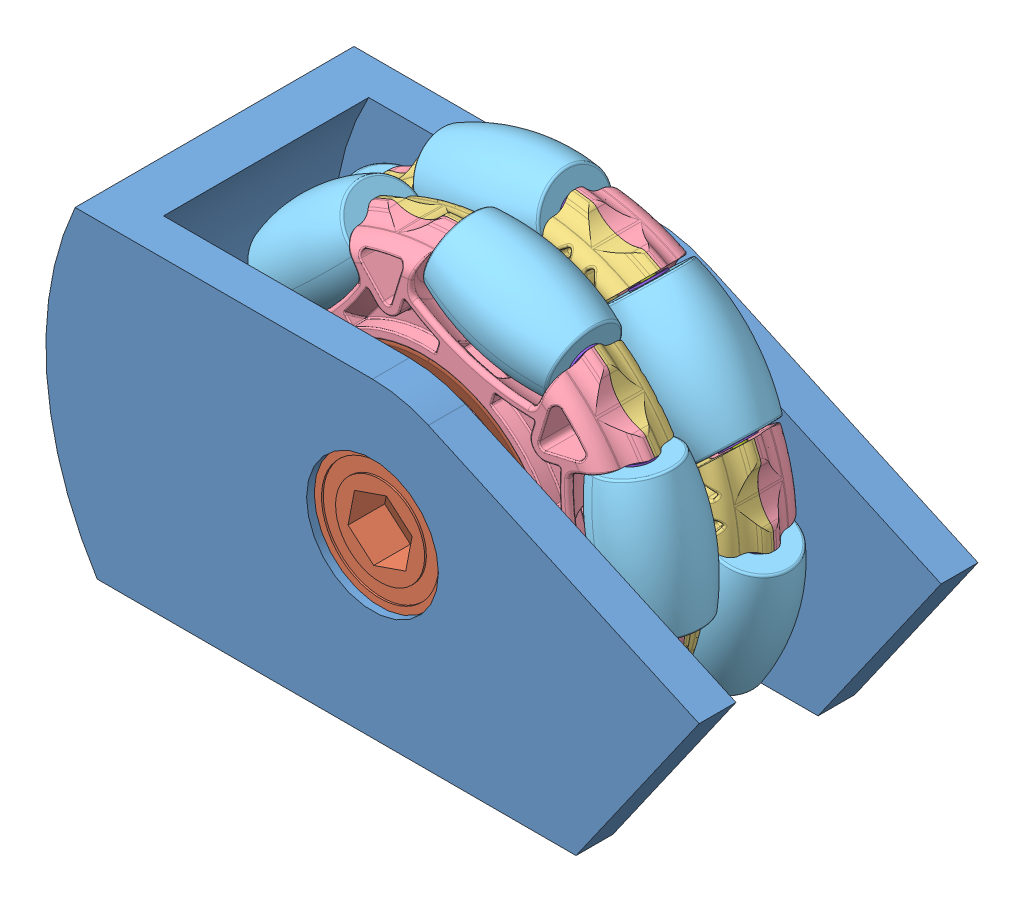
SolidWorks assembly Assem3, configuration Default. Lengths in mm.
Overall size (153.65 153.65 60.45).
87 component instances, 11 part files, 11 mates.
Components (placement in the parent):
- OuterWheelBase-1: OuterWheelBase [Default] at (20.5301 83.2781 119.3728) size (141.6 67.39 60.45)
- 0_500_Hex_ID_x_1_125_OD_x_0_313_WD_Flanged_Bearing_v2_217-3875 (1).step-1: 0_500_Hex_ID_x_1_125_OD_x_0_313_WD_Flanged_Bearing_v2_217-3875 (1).step [Default] at (20.5301 83.2781 125.7228) x (0.944813 0.327609 0) z (-0.327609 0.944813 0) size (31.12 7.94 31.12)
- 0_500_Hex_ID_x_1_125_OD_x_0_313_WD_Flanged_Bearing_v2_217-3875 (1).step-2: 0_500_Hex_ID_x_1_125_OD_x_0_313_WD_Flanged_Bearing_v2_217-3875 (1).step [Default] at (20.5301 83.2781 68.5728) x (0.995254 0.097311 0) z (0.097311 -0.995254 0) size (31.12 7.94 31.12)
- 4_Omni-Directional_Wheel_v2_276-6194.STEP-1: 4_Omni-Directional_Wheel_v2_276-6194.STEP [Default] at (20.5301 83.2781 97.2714) x (0.956229 -0.29262 0) z (0 0 1) size (126.87 125.33 42.82)
  - 217-6194-002 Rev5.STEP-1: 217-6194-002 Rev5.STEP [Default] at origin size (94.42 94.42 19.26)
  - 217-6194-003 Rev8.STEP-1: 217-6194-003 Rev8.STEP [Default] at (0 0 9.525) size (94.42 90.2 19.97)
  - 217-6194-003 Rev8.STEP-2: 217-6194-003 Rev8.STEP [Default] at (0 0 -9.525) x (-0.866025 0.5 0) z (0 0 -1) size (94.42 90.2 19.97)
  - 217-6194-001 Rev3.STEP-1: 217-6194-001 Rev3.STEP [Default] at (0 -40.8953 9.525) x (1 0 0) z (0 0.225507 0.974241) size (28 19.81 19.81)
  - 217-6194-008 Rev4.STEP-1: 217-6194-008 Rev4.STEP [Default] at (0 -40.8953 9.525) x (0 0.977486 -0.211002) z (0 0.211002 0.977486) size (4.05 28 4.05)
  - 217-6194-004 Rev4.STEP-1: 217-6194-004 Rev4.STEP [Default] at (0 -40.8953 9.525) size (33.5 3 3)
  - 217-2584-009 Rev1.STEP-1: 217-2584-009 Rev1.STEP [Default] at (14.38 -40.8953 9.525) x (0 0.996349 0.085373) z (0 -0.085373 0.996349) size (7 0.38 7)
  - 217-2584-009 Rev1.STEP-2: 217-2584-009 Rev1.STEP [Default] at (-14 -40.8953 9.525) x (0 0.996349 0.085373) z (0 -0.085373 0.996349) size (7 0.38 7)
  - 217-6194-004 Rev4.STEP-2: 217-6194-004 Rev4.STEP [Default] at (-20.4477 -35.4164 -9.525) x (0.866025 -0.5 0) z (0 0 1) size (33.5 3 3)
  - 217-6194-008 Rev4.STEP-2: 217-6194-008 Rev4.STEP [Default] at (-20.4477 -35.4164 -9.525) x (0.488743 0.846527 -0.211002) z (0.105501 0.182733 0.977486) size (4.05 28 4.05)
  - 217-6194-001 Rev3.STEP-2: 217-6194-001 Rev3.STEP [Default] at (-20.4477 -35.4164 -9.525) x (0.866025 -0.5 0) z (0.112754 0.195295 0.974241) size (28 19.81 19.81)
  - 217-2584-009 Rev1.STEP-3: 217-2584-009 Rev1.STEP [Default] at (-7.9942 -42.6064 -9.525) x (0.498175 0.862864 0.085373) z (-0.042686 -0.073935 0.996349) size (7 0.38 7)
  - 217-2584-009 Rev1.STEP-4: 217-2584-009 Rev1.STEP [Default] at (-32.572 -28.4164 -9.525) x (0.498175 0.862864 0.085373) z (-0.042686 -0.073935 0.996349) size (7 0.38 7)
  - 217-6194-005 Rev1.STEP-1: 217-6194-005 Rev1.STEP [Default] at (6.1631 -23.0011 0) x (0.707107 -0.707107 0) z (0.707107 0.707107 0) size (7.34 25.4 7.34)
  - 217-6194-005 Rev1.STEP-2: 217-6194-005 Rev1.STEP [Default] at (23.0011 -6.1631 0) x (0.965926 0.258819 0) z (-0.258819 0.965926 0) size (7.34 25.4 7.34)
  - 217-6194-005 Rev1.STEP-3: 217-6194-005 Rev1.STEP [Default] at (16.838 16.838 0) x (0.258819 0.965926 0) z (-0.965926 0.258819 0) size (7.34 25.4 7.34)
  - 217-6194-005 Rev1.STEP-4: 217-6194-005 Rev1.STEP [Default] at (-6.1631 23.0011 0) x (-0.707107 0.707107 0) z (-0.707107 -0.707107 0) size (7.34 25.4 7.34)
  - 217-6194-005 Rev1.STEP-5: 217-6194-005 Rev1.STEP [Default] at (-23.0011 6.1631 0) x (-0.965926 -0.258819 0) z (0.258819 -0.965926 0) size (7.34 25.4 7.34)
  - 217-6194-005 Rev1.STEP-6: 217-6194-005 Rev1.STEP [Default] at (-16.838 -16.838 0) x (-0.258819 -0.965926 0) z (0.965926 -0.258819 0) size (7.34 25.4 7.34)
  - 217-2584-009 Rev1.STEP-5: 217-2584-009 Rev1.STEP [Default] at (8.3233 -42.4164 -9.525) x (-0.498175 0.862864 0.085373) z (0.042686 -0.073935 0.996349) size (7 0.38 7)
  - 217-2584-009 Rev1.STEP-6: 217-2584-009 Rev1.STEP [Default] at (40.8953 -14 -9.525) x (-0.996349 0 0.085373) z (0.085373 0 0.996349) size (7 0.38 7)
  - 217-2584-009 Rev1.STEP-7: 217-2584-009 Rev1.STEP [Default] at (32.572 28.4164 -9.525) x (-0.498175 -0.862864 0.085373) z (0.042686 0.073935 0.996349) size (7 0.38 7)
  - 217-2584-009 Rev1.STEP-8: 217-2584-009 Rev1.STEP [Default] at (-8.3233 42.4164 -9.525) x (0.498175 -0.862864 0.085373) z (-0.042686 0.073935 0.996349) size (7 0.38 7)
  - 217-2584-009 Rev1.STEP-9: 217-2584-009 Rev1.STEP [Default] at (-40.8953 14 -9.525) x (0.996349 0 0.085373) z (-0.085373 0 0.996349) size (7 0.38 7)
  - 217-2584-009 Rev1.STEP-10: 217-2584-009 Rev1.STEP [Default] at (32.9011 -28.2264 -9.525) x (-0.498175 0.862864 0.085373) z (0.042686 -0.073935 0.996349) size (7 0.38 7)
  - 217-2584-009 Rev1.STEP-11: 217-2584-009 Rev1.STEP [Default] at (40.8953 14.38 -9.525) x (-0.996349 0 0.085373) z (0.085373 0 0.996349) size (7 0.38 7)
  - 217-2584-009 Rev1.STEP-12: 217-2584-009 Rev1.STEP [Default] at (7.9942 42.6064 -9.525) x (-0.498175 -0.862864 0.085373) z (0.042686 0.073935 0.996349) size (7 0.38 7)
  - 217-2584-009 Rev1.STEP-13: 217-2584-009 Rev1.STEP [Default] at (-32.9011 28.2264 -9.525) x (0.498175 -0.862864 0.085373) z (-0.042686 0.073935 0.996349) size (7 0.38 7)
  - 217-2584-009 Rev1.STEP-14: 217-2584-009 Rev1.STEP [Default] at (-40.8953 -14.38 -9.525) x (0.996349 0 0.085373) z (-0.085373 0 0.996349) size (7 0.38 7)
  - 217-6194-001 Rev3.STEP-3: 217-6194-001 Rev3.STEP [Default] at (20.4477 -35.4164 -9.525) x (0.866025 0.5 0) z (-0.112754 0.195295 0.974241) size (28 19.81 19.81)
  - 217-6194-001 Rev3.STEP-4: 217-6194-001 Rev3.STEP [Default] at (40.8953 0 -9.525) x (0 1 0) z (-0.225507 0 0.974241) size (28 19.81 19.81)
  - 217-6194-001 Rev3.STEP-5: 217-6194-001 Rev3.STEP [Default] at (20.4477 35.4164 -9.525) x (-0.866025 0.5 0) z (-0.112754 -0.195295 0.974241) size (28 19.81 19.81)
  - 217-6194-001 Rev3.STEP-6: 217-6194-001 Rev3.STEP [Default] at (-20.4477 35.4164 -9.525) x (-0.866025 -0.5 0) z (0.112754 -0.195295 0.974241) size (28 19.81 19.81)
  - 217-6194-001 Rev3.STEP-7: 217-6194-001 Rev3.STEP [Default] at (-40.8953 0 -9.525) x (0 -1 0) z (0.225507 0 0.974241) size (28 19.81 19.81)
  - 217-6194-008 Rev4.STEP-3: 217-6194-008 Rev4.STEP [Default] at (20.4477 -35.4164 -9.525) x (-0.488743 0.846527 -0.211002) z (-0.105501 0.182733 0.977486) size (4.05 28 4.05)
  - 217-6194-008 Rev4.STEP-4: 217-6194-008 Rev4.STEP [Default] at (40.8953 0 -9.525) x (-0.977486 0 -0.211002) z (-0.211002 0 0.977486) size (4.05 28 4.05)
  - 217-6194-008 Rev4.STEP-5: 217-6194-008 Rev4.STEP [Default] at (20.4477 35.4164 -9.525) x (-0.488743 -0.846527 -0.211002) z (-0.105501 -0.182733 0.977486) size (4.05 28 4.05)
  - 217-6194-008 Rev4.STEP-6: 217-6194-008 Rev4.STEP [Default] at (-20.4477 35.4164 -9.525) x (0.488743 -0.846527 -0.211002) z (0.105501 -0.182733 0.977486) size (4.05 28 4.05)
  - 217-6194-008 Rev4.STEP-7: 217-6194-008 Rev4.STEP [Default] at (-40.8953 0 -9.525) x (0.977486 0 -0.211002) z (0.211002 0 0.977486) size (4.05 28 4.05)
  - 217-6194-004 Rev4.STEP-3: 217-6194-004 Rev4.STEP [Default] at (20.4477 -35.4164 -9.525) x (0.866025 0.5 0) z (0 0 1) size (33.5 3 3)
  - 217-6194-004 Rev4.STEP-4: 217-6194-004 Rev4.STEP [Default] at (40.8953 0 -9.525) x (0 1 0) z (0 0 1) size (33.5 3 3)
  - 217-6194-004 Rev4.STEP-5: 217-6194-004 Rev4.STEP [Default] at (20.4477 35.4164 -9.525) x (-0.866025 0.5 0) z (0 0 1) size (33.5 3 3)
  - 217-6194-004 Rev4.STEP-6: 217-6194-004 Rev4.STEP [Default] at (-20.4477 35.4164 -9.525) x (-0.866025 -0.5 0) z (0 0 1) size (33.5 3 3)
  - 217-6194-004 Rev4.STEP-7: 217-6194-004 Rev4.STEP [Default] at (-40.8953 0 -9.525) x (0 -1 0) z (0 0 1) size (33.5 3 3)
  - 217-2584-009 Rev1.STEP-15: 217-2584-009 Rev1.STEP [Default] at (28.4164 -32.572 9.525) x (-0.862864 0.498175 0.085373) z (0.073935 -0.042686 0.996349) size (7 0.38 7)
  - 217-2584-009 Rev1.STEP-16: 217-2584-009 Rev1.STEP [Default] at (42.4164 8.3233 9.525) x (-0.862864 -0.498175 0.085373) z (0.073935 0.042686 0.996349) size (7 0.38 7)
  - 217-2584-009 Rev1.STEP-17: 217-2584-009 Rev1.STEP [Default] at (14 40.8953 9.525) x (0 -0.996349 0.085373) z (0 0.085373 0.996349) size (7 0.38 7)
  - 217-2584-009 Rev1.STEP-18: 217-2584-009 Rev1.STEP [Default] at (-28.4164 32.572 9.525) x (0.862864 -0.498175 0.085373) z (-0.073935 0.042686 0.996349) size (7 0.38 7)
  - 217-2584-009 Rev1.STEP-19: 217-2584-009 Rev1.STEP [Default] at (-42.4164 -8.3233 9.525) x (0.862864 0.498175 0.085373) z (-0.073935 -0.042686 0.996349) size (7 0.38 7)
  - 217-2584-009 Rev1.STEP-20: 217-2584-009 Rev1.STEP [Default] at (42.6064 -7.9942 9.525) x (-0.862864 0.498175 0.085373) z (0.073935 -0.042686 0.996349) size (7 0.38 7)
  - 217-2584-009 Rev1.STEP-21: 217-2584-009 Rev1.STEP [Default] at (28.2264 32.9011 9.525) x (-0.862864 -0.498175 0.085373) z (0.073935 0.042686 0.996349) size (7 0.38 7)
  - 217-2584-009 Rev1.STEP-22: 217-2584-009 Rev1.STEP [Default] at (-14.38 40.8953 9.525) x (0 -0.996349 0.085373) z (0 0.085373 0.996349) size (7 0.38 7)
  - 217-2584-009 Rev1.STEP-23: 217-2584-009 Rev1.STEP [Default] at (-42.6064 7.9942 9.525) x (0.862864 -0.498175 0.085373) z (-0.073935 0.042686 0.996349) size (7 0.38 7)
  - 217-2584-009 Rev1.STEP-24: 217-2584-009 Rev1.STEP [Default] at (-28.2264 -32.9011 9.525) x (0.862864 0.498175 0.085373) z (-0.073935 -0.042686 0.996349) size (7 0.38 7)
  - 217-6194-004 Rev4.STEP-8: 217-6194-004 Rev4.STEP [Default] at (35.4164 -20.4477 9.525) x (0.5 0.866025 0) z (0 0 1) size (33.5 3 3)
  - 217-6194-004 Rev4.STEP-9: 217-6194-004 Rev4.STEP [Default] at (35.4164 20.4477 9.525) x (-0.5 0.866025 0) z (0 0 1) size (33.5 3 3)
  - 217-6194-004 Rev4.STEP-10: 217-6194-004 Rev4.STEP [Default] at (0 40.8953 9.525) x (-1 0 0) z (0 0 1) size (33.5 3 3)
  - 217-6194-004 Rev4.STEP-11: 217-6194-004 Rev4.STEP [Default] at (-35.4164 20.4477 9.525) x (-0.5 -0.866025 0) z (0 0 1) size (33.5 3 3)
  - 217-6194-004 Rev4.STEP-12: 217-6194-004 Rev4.STEP [Default] at (-35.4164 -20.4477 9.525) x (0.5 -0.866025 0) z (0 0 1) size (33.5 3 3)
  - 217-6194-008 Rev4.STEP-8: 217-6194-008 Rev4.STEP [Default] at (35.4164 -20.4477 9.525) x (-0.846527 0.488743 -0.211002) z (-0.182733 0.105501 0.977486) size (4.05 28 4.05)
  - 217-6194-008 Rev4.STEP-9: 217-6194-008 Rev4.STEP [Default] at (35.4164 20.4477 9.525) x (-0.846527 -0.488743 -0.211002) z (-0.182733 -0.105501 0.977486) size (4.05 28 4.05)
  - 217-6194-008 Rev4.STEP-10: 217-6194-008 Rev4.STEP [Default] at (0 40.8953 9.525) x (0 -0.977486 -0.211002) z (0 -0.211002 0.977486) size (4.05 28 4.05)
  - 217-6194-008 Rev4.STEP-11: 217-6194-008 Rev4.STEP [Default] at (-35.4164 20.4477 9.525) x (0.846527 -0.488743 -0.211002) z (0.182733 -0.105501 0.977486) size (4.05 28 4.05)
  - 217-6194-008 Rev4.STEP-12: 217-6194-008 Rev4.STEP [Default] at (-35.4164 -20.4477 9.525) x (0.846527 0.488743 -0.211002) z (0.182733 0.105501 0.977486) size (4.05 28 4.05)
  - 217-6194-001 Rev3.STEP-8: 217-6194-001 Rev3.STEP [Default] at (35.4164 -20.4477 9.525) x (0.5 0.866025 0) z (-0.195295 0.112754 0.974241) size (28 19.81 19.81)
  - 217-6194-001 Rev3.STEP-9: 217-6194-001 Rev3.STEP [Default] at (35.4164 20.4477 9.525) x (-0.5 0.866025 0) z (-0.195295 -0.112754 0.974241) size (28 19.81 19.81)
  - 217-6194-001 Rev3.STEP-10: 217-6194-001 Rev3.STEP [Default] at (0 40.8953 9.525) x (-1 0 0) z (0 -0.225507 0.974241) size (28 19.81 19.81)
  - 217-6194-001 Rev3.STEP-11: 217-6194-001 Rev3.STEP [Default] at (-35.4164 20.4477 9.525) x (-0.5 -0.866025 0) z (0.195295 -0.112754 0.974241) size (28 19.81 19.81)
  - 217-6194-001 Rev3.STEP-12: 217-6194-001 Rev3.STEP [Default] at (-35.4164 -20.4477 9.525) x (0.5 -0.866025 0) z (0.195295 0.112754 0.974241) size (28 19.81 19.81)
  - 217-4775-008 Rev1_90116A020.STEP-1: 217-4775-008 Rev1_90116A020.STEP [Default] at (0 -40 -2.025) x (-0.89498 0.446105 0) z (0 0 -1) size (4.2 4.2 11.62)
  - 217-4775-008 Rev1_90116A020.STEP-2: 217-4775-008 Rev1_90116A020.STEP [Default] at (20 -34.641 2.025) x (0.648091 0.761563 0) z (0 0 1) size (4.2 4.2 11.62)
  - 217-4775-008 Rev1_90116A020.STEP-3: 217-4775-008 Rev1_90116A020.STEP [Default] at (40 0 2.025) x (-0.335487 0.942045 0) z (0 0 1) size (4.2 4.2 11.62)
  - 217-4775-008 Rev1_90116A020.STEP-4: 217-4775-008 Rev1_90116A020.STEP [Default] at (20 34.641 2.025) x (-0.983578 0.180482 0) z (0 0 1) size (4.2 4.2 11.62)
  - 217-4775-008 Rev1_90116A020.STEP-5: 217-4775-008 Rev1_90116A020.STEP [Default] at (-20 34.641 2.025) x (-0.648091 -0.761563 0) z (0 0 1) size (4.2 4.2 11.62)
  - 217-4775-008 Rev1_90116A020.STEP-6: 217-4775-008 Rev1_90116A020.STEP [Default] at (-40 0 2.025) x (0.335487 -0.942045 0) z (0 0 1) size (4.2 4.2 11.62)
  - 217-4775-008 Rev1_90116A020.STEP-7: 217-4775-008 Rev1_90116A020.STEP [Default] at (-20 -34.641 2.025) x (0.983578 -0.180482 0) z (0 0 1) size (4.2 4.2 11.62)
  - 217-4775-008 Rev1_90116A020.STEP-8: 217-4775-008 Rev1_90116A020.STEP [Default] at (34.641 -20 -2.025) x (-0.833829 -0.552023 0) z (0 0 -1) size (4.2 4.2 11.62)
  - 217-4775-008 Rev1_90116A020.STEP-9: 217-4775-008 Rev1_90116A020.STEP [Default] at (34.641 20 -2.025) x (0.061152 -0.998128 0) z (0 0 -1) size (4.2 4.2 11.62)
  - 217-4775-008 Rev1_90116A020.STEP-10: 217-4775-008 Rev1_90116A020.STEP [Default] at (0 40 -2.025) x (0.89498 -0.446105 0) z (0 0 -1) size (4.2 4.2 11.62)
  - 217-4775-008 Rev1_90116A020.STEP-11: 217-4775-008 Rev1_90116A020.STEP [Default] at (-34.641 20 -2.025) x (0.833829 0.552023 0) z (0 0 -1) size (4.2 4.2 11.62)
  - 217-4775-008 Rev1_90116A020.STEP-12: 217-4775-008 Rev1_90116A020.STEP [Default] at (-34.641 -20 -2.025) x (-0.061152 0.998128 0) z (0 0 -1) size (4.2 4.2 11.62)
- 1_2_Hex_Bore_Aluminum_VersaHub_217-2592 (1).step-1: 1_2_Hex_Bore_Aluminum_VersaHub_217-2592 (1).step [Default] at (20.5301 83.2781 90.9214) x (0 0 -1) z (0.999382 -0.035159 0) size (12.7 55.88 55.88)
- 1_2_Hex_Bore_Aluminum_VersaHub_217-2592 (1).step-2: 1_2_Hex_Bore_Aluminum_VersaHub_217-2592 (1).step [Default] at (20.5301 83.2781 103.6214) x (0 0 1) z (-0.999382 0.035159 0) size (12.7 55.88 55.88)
Mates (geometry in assembly coordinates):
- Concentric1: concentric: cylinder of OuterWheelBase-1 through (20.5301 83.2781 127.3728) axis (0 0 -1) radius 14.2875; cylinder of 0_500_Hex_ID_x_1_125_OD_x_0_313_WD_Flanged_Bearing_v2_217-3875 (1).step-1 through (20.5301 83.2781 125.7228) axis (0 0 -1) radius 14.2748
- Concentric2: concentric: cylinder of OuterWheelBase-1 through (20.5301 83.2781 66.9228) axis (0 0 1) radius 14.2875; cylinder of 0_500_Hex_ID_x_1_125_OD_x_0_313_WD_Flanged_Bearing_v2_217-3875 (1).step-2 through (20.5301 83.2781 68.5728) axis (0 0 1) radius 14.2748
- Coincident1: coincident: plane of OuterWheelBase-1 through (20.5301 83.2781 119.3728) normal (0 0 -1); plane of 0_500_Hex_ID_x_1_125_OD_x_0_313_WD_Flanged_Bearing_v2_217-3875 (1).step-1 through (35.229 88.3749 119.3728) normal (0 0 1)
- Coincident2: coincident: plane of OuterWheelBase-1 through (20.5301 83.2781 74.9228) normal (0 0 1); plane of 0_500_Hex_ID_x_1_125_OD_x_0_313_WD_Flanged_Bearing_v2_217-3875 (1).step-2 through (36.0137 84.792 74.9228) normal (0 0 -1)
- Concentric3: concentric: cylinder of 4_Omni-Directional_Wheel_v2_276-6194.STEP-1/217-6194-003 Rev8.STEP-2 through (20.5301 83.2781 81.3964) axis (0 0 1) radius 14.3; cylinder of 1_2_Hex_Bore_Aluminum_VersaHub_217-2592 (1).step-1 through (20.5301 83.2781 78.2214) axis (0 0 -1) radius 14.2949
- Concentric4: concentric: cylinder of 4_Omni-Directional_Wheel_v2_276-6194.STEP-1/217-6194-003 Rev8.STEP-2 through (21.3673 107.0759 84.5714) axis (0 0 -1) radius 2.1526; cylinder of 1_2_Hex_Bore_Aluminum_VersaHub_217-2592 (1).step-1 through (21.3673 107.0759 164.0147) axis (0 0 -1) radius 2.15
- Concentric5: concentric: cylinder of 4_Omni-Directional_Wheel_v2_276-6194.STEP-1/217-6194-003 Rev8.STEP-1 through (20.5301 83.2781 113.1464) axis (0 0 -1) radius 14.3; cylinder of 1_2_Hex_Bore_Aluminum_VersaHub_217-2592 (1).step-2 through (20.5301 83.2781 116.3214) axis (0 0 1) radius 14.2949
- Concentric6: concentric: cylinder of 4_Omni-Directional_Wheel_v2_276-6194.STEP-1/217-6194-003 Rev8.STEP-1 through (0.3392 95.9021 109.9714) axis (0 0 1) radius 2.1526; cylinder of 1_2_Hex_Bore_Aluminum_VersaHub_217-2592 (1).step-2 through (0.3392 95.9021 30.528) axis (0 0 1) radius 2.15
- Coincident3: coincident: plane of 4_Omni-Directional_Wheel_v2_276-6194.STEP-1/217-6194-003 Rev8.STEP-1 through (20.5301 83.2781 113.1464) normal (0 0 1); plane of 1_2_Hex_Bore_Aluminum_VersaHub_217-2592 (1).step-2 through (21.0327 97.5642 113.1464) normal (0 0 -1)
- Coincident4: coincident: plane of 4_Omni-Directional_Wheel_v2_276-6194.STEP-1/217-6194-003 Rev8.STEP-2 through (20.5301 83.2781 81.3964) normal (0 0 -1); plane of 1_2_Hex_Bore_Aluminum_VersaHub_217-2592 (1).step-1 through (21.0327 97.5642 81.3964) normal (0 0 1)
- Concentric7: concentric: cylinder of OuterWheelBase-1 through (20.5301 83.2781 66.9228) axis (0 0 1) radius 14.2875; circle of 1_2_Hex_Bore_Aluminum_VersaHub_217-2592 (1).step-1
